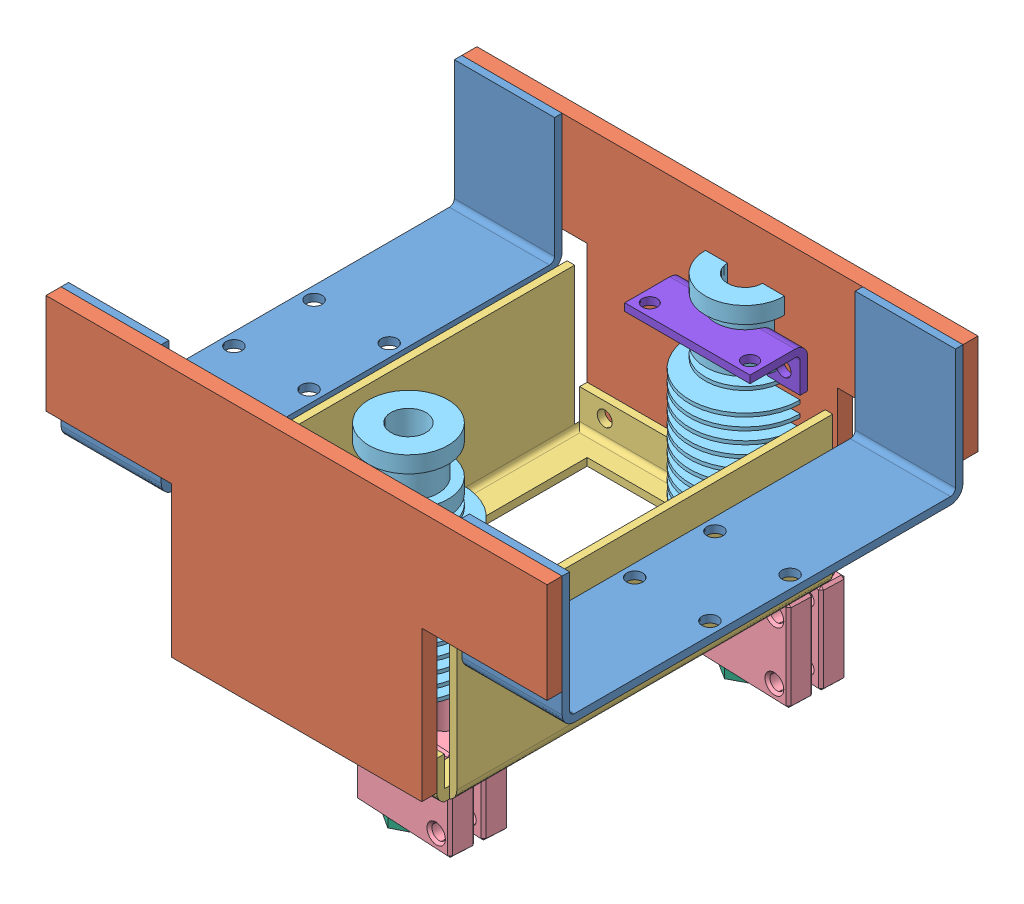
SolidWorks assembly dual-extruder, configuration Default. Lengths in mm.
Overall size (100 79.7 96.79).
16 component instances, 8 part files, 16 mates.
Components (placement in the parent):
- h-mount-1: h-mount [Default] at (27.3857 46.8236 78.344) size (20 26.5 80)
- dual-layer-side-plate-1: dual-layer-side-plate [Default] at (67.3857 48.3236 35.344) size (100 50 3)
- h-mount-2: h-mount [Default] at (107.3857 46.8236 78.344) size (20 26.5 80)
- dual-layer-side-plate-2: dual-layer-side-plate [Default] at (67.3857 48.3236 118.344) size (100 50 3)
- bottom-plate-1: bottom-plate [Default] at (67.3857 20.8236 78.344) x (0 0 1) z (-1 0 0) size (80 30 53)
- Hotend Volcano J-head V6-1: Hotend Volcano J-head V6 [Valor predeterminado] at (69.0876 -1.179 32.5693) x (-0.035658 0 0.999364) z (0 1 0) size (26.65 28.32 70.3)
  - Bloco Aquecedor-1: Bloco Aquecedor [Valor predeterminado] at origin size (11.2 20 20)
  - Dissipador-1: Dissipador [Valor predeterminado] at (0.7469 3.7969 -4) x (0 0 -1) z (0.240623 -0.970619 0) size (41.1 22 22)
  - Bico 0.4mm-1: Bico 0.4mm [Valor predeterminado] x (-1 0 0) z (0 0 -1) size (7.85 6.8 5.2)
  - Tubo conector-1: Tubo conector [Valor predeterminado] at (0.7469 3.7969 24) x (-0.240623 0.970619 0) z (0 0 -1) size (6.8 6.8 4)
- Hotend Volcano J-head V6-2: Hotend Volcano J-head V6 [Valor predeterminado] at (63.3835 0.7756 93.8327) x (-0.054092 0 0.998536) z (0 1 0) size (26.65 28.32 70.3)
  - Bloco Aquecedor-1: Bloco Aquecedor [Valor predeterminado] at origin size (11.2 20 20)
  - Dissipador-1: Dissipador [Valor predeterminado] at (0.7469 3.7969 -4) x (0 0 -1) z (0.240623 -0.970619 0) size (41.1 22 22)
  - Bico 0.4mm-1: Bico 0.4mm [Valor predeterminado] x (-1 0 0) z (0 0 -1) size (7.85 6.8 5.2)
  - Tubo conector-1: Tubo conector [Valor predeterminado] at (0.7469 3.7969 24) x (-0.240623 0.970619 0) z (0 0 -1) size (6.8 6.8 4)
- hotend-mount-bracket-1: hotend-mount-bracket [Default] at (73.8847 56.8113 44.094) size (25 8.5 11.5)
Mates (geometry in assembly coordinates):
- Coincident1: coincident anti-aligned: plane of dual-layer-side-plate-1 through (67.3857 48.3236 38.344) normal (0 0 1); plane of h-mount-1 through (17.3857 48.3236 38.344) normal (0 0 -1)
- Coincident3: coincident aligned: plane of h-mount-1 through (17.3857 48.3236 38.344) normal (-1 0 0); plane of dual-layer-side-plate-1 through (17.3857 73.3236 38.344) normal (-1 0 0)
- Coincident4: coincident aligned: plane of h-mount-1 through (27.3857 73.3236 78.344) normal (0 1 0); plane of dual-layer-side-plate-1 through (17.3857 73.3236 38.344) normal (0 1 0)
- Coincident5: coincident anti-aligned: plane of dual-layer-side-plate-1 through (67.3857 48.3236 38.344) normal (0 0 1); plane of h-mount-2 through (97.3857 48.3236 38.344) normal (0 0 -1)
- Coincident7: coincident aligned: plane of dual-layer-side-plate-1 through (17.3857 73.3236 38.344) normal (0 1 0); plane of h-mount-2 through (107.3857 73.3236 78.344) normal (0 1 0)
- Coincident8: coincident aligned: plane of dual-layer-side-plate-1 through (117.3857 73.3236 38.344) normal (1 0 0); plane of h-mount-2 through (117.3857 48.3236 38.344) normal (1 0 0)
- Coincident9: coincident aligned: plane of h-mount-1 through (27.3857 73.3236 78.344) normal (0 1 0); plane of dual-layer-side-plate-2 through (17.3857 73.3236 121.344) normal (0 1 0)
- Coincident10: coincident anti-aligned: plane of h-mount-1 through (17.3857 48.3236 118.344) normal (0 0 1); plane of dual-layer-side-plate-2 through (67.3857 48.3236 118.344) normal (0 0 -1)
- Coincident11: coincident aligned: plane of h-mount-1 through (17.3857 48.3236 38.344) normal (-1 0 0); plane of dual-layer-side-plate-2 through (17.3857 73.3236 121.344) normal (-1 0 0)
- Coincident12: coincident anti-aligned: plane of dual-layer-side-plate-1 through (67.3857 48.3236 38.344) normal (0 0 1); plane of bottom-plate-1 through (92.3857 22.3236 38.344) normal (0 0 -1)
- Coincident13: coincident aligned: plane of dual-layer-side-plate-1 through (42.3857 53.3236 38.344) normal (-1 0 0); plane of bottom-plate-1 through (42.3857 22.3236 38.344) normal (-1 0 0)
- Coincident14: coincident aligned: plane of dual-layer-side-plate-1 through (42.3857 23.3236 38.344) normal (0 -1 0); line of bottom-plate-1 through (92.3857 23.3236 38.344) axis (-1 0 0)
- Parallel1: parallel aligned: plane of Hotend Volcano J-head V6-1/Bloco Aquecedor-1 through (73.2275 -1.179 56.6862) normal (0 -1 0); plane of Hotend Volcano J-head V6-2/Bloco Aquecedor-1 through (75.6122 0.7756 100.1034) normal (0 -1 0)
- Parallel2: parallel aligned: plane of h-mount-2 through (107.3857 46.8236 78.344) normal (0 -1 0); plane of Hotend Volcano J-head V6-2/Bloco Aquecedor-1 through (75.6122 0.7756 100.1034) normal (0 -1 0)
- Coincident17: coincident anti-aligned: plane of dual-layer-side-plate-1 through (67.3857 48.3236 38.344) normal (0 0 1); plane of hotend-mount-bracket-1 through (61.3847 58.3113 38.344) normal (0 0 -1)
- Concentric1: concentric aligned: cylinder of Hotend Volcano J-head V6-1/Dissipador-1 through (73.8847 22.821 38.344) axis (0 -1 0) radius 5.9; cylinder of hotend-mount-bracket-1 through (73.8847 58.3113 38.344) axis (0 -1 0) radius 5.9
